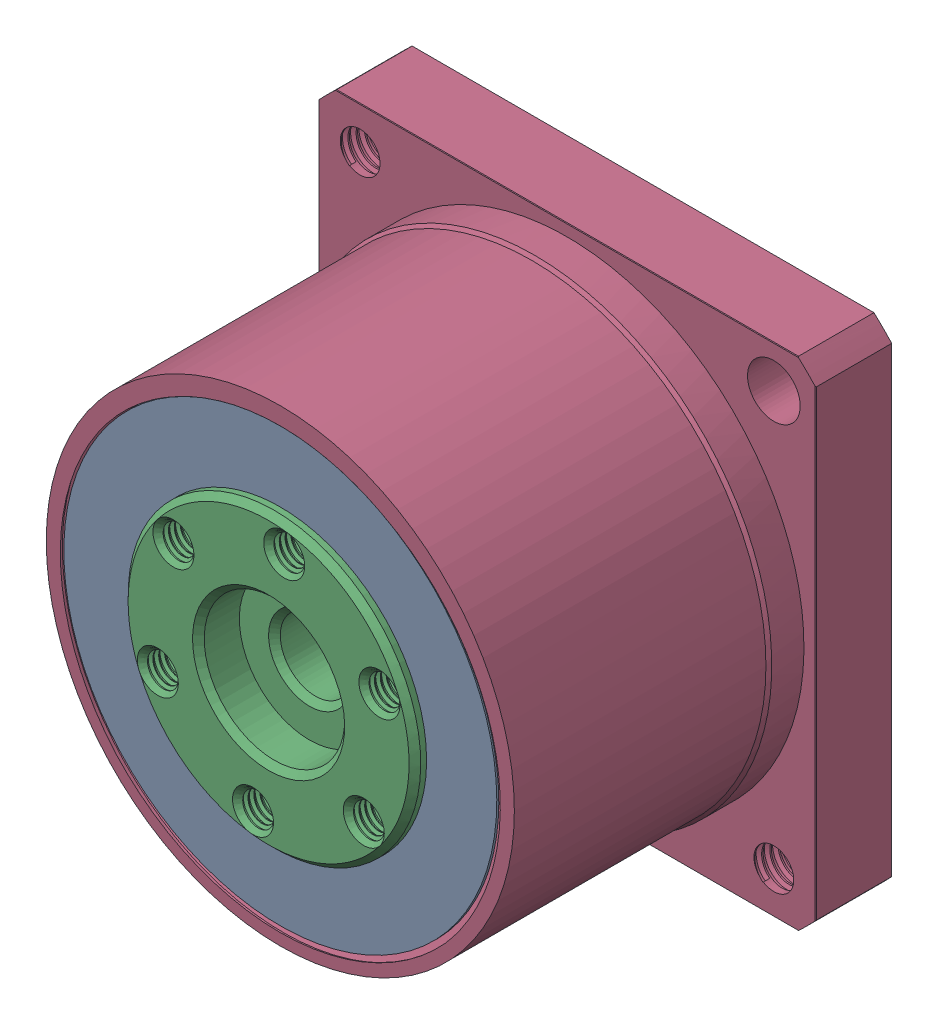
SolidWorks assembly MINIF11, configuration 默认. Lengths in mm.
Overall size (71.06 71.06 35.75).
13 component instances, 13 part files, 0 mates.
Components (placement in the parent):
- MINIF11步进电机42安装案例-Part-4-1: MINIF11步进电机42安装案例-Part-4 [默认] at (0 -8.5 -3) x (1 0 0) z (0 -1 0) size (3.05 3 6.07)
- MINIF11步进电机42安装案例-Part-6-1: MINIF11步进电机42安装案例-Part-6 [默认] at (0 0 -9.6) x (0.923728 0.383049 0) z (0 0 -1) size (18 18 5.5)
- MINIF11步进电机42安装案例-Part-7-1: MINIF11步进电机42安装案例-Part-7 [默认] at (0 0 -9.6) x (0.923728 0.383049 0) z (0 0 -1) size (31 31 13.65)
- MINIF11步进电机42安装案例-Part-8-1: MINIF11步进电机42安装案例-Part-8 [默认] at (0 0 -9.6) x (0.923728 0.383049 0) z (0 0 -1) size (54.38 54.38 31.61)
- MINIF11步进电机42安装案例-Part-9-1: MINIF11步进电机42安装案例-Part-9 [默认] at (0 0 -9.6) x (0.923728 0.383049 0) z (0 0 -1) size (27.26 27.26 4.6)
- MINIF11步进电机42安装案例-Part-10-1: MINIF11步进电机42安装案例-Part-10 [默认] at (0 0 -9.6) x (0.923728 0.383049 0) z (0 0 -1) size (21.93 21.93 4.8)
- MINIF11步进电机42安装案例-Part-11-1: MINIF11步进电机42安装案例-Part-11 [默认] at (0 0 -9.6) x (0.923728 0.383049 0) z (0 0 -1) size (24.5 24.5 13.35)
- MINIF11步进电机42安装案例-Part-12-1: MINIF11步进电机42安装案例-Part-12 [默认] at (0 0 -9.6) x (0.923728 0.383049 0) z (0 0 -1) size (6.46 4.9 3.1)
- MINIF11步进电机42安装案例-Part-13-1: MINIF11步进电机42安装案例-Part-13 [默认] at (0 0 -9.6) x (0.923728 0.383049 0) z (0 0 -1) size (5.6 5.6 11)
- MINIF11步进电机42安装案例-Part-14-1: MINIF11步进电机42安装案例-Part-14 [默认] at (0 0 -9.6) x (0.923728 0.383049 0) z (0 0 -1) size (35 35 7)
- MINIF11步进电机42安装案例-Part-15-1: MINIF11步进电机42安装案例-Part-15 [默认] at (0 0 -9.6) x (0.923728 0.383049 0) z (0 0 -1) size (5.6 5.6 11)
- MINIF11步进电机42安装案例-Part-16-1: MINIF11步进电机42安装案例-Part-16 [默认] at (0 0 -9.6) x (0.923728 0.383049 0) z (0 0 -1) size (29.2 29.2 20)
- MINIF11步进电机42安装案例-Part-17-1: MINIF11步进电机42安装案例-Part-17 [默认] at (0 0 -9.6) x (0.923728 0.383049 0) z (0 0 -1) size (37 37 11)
